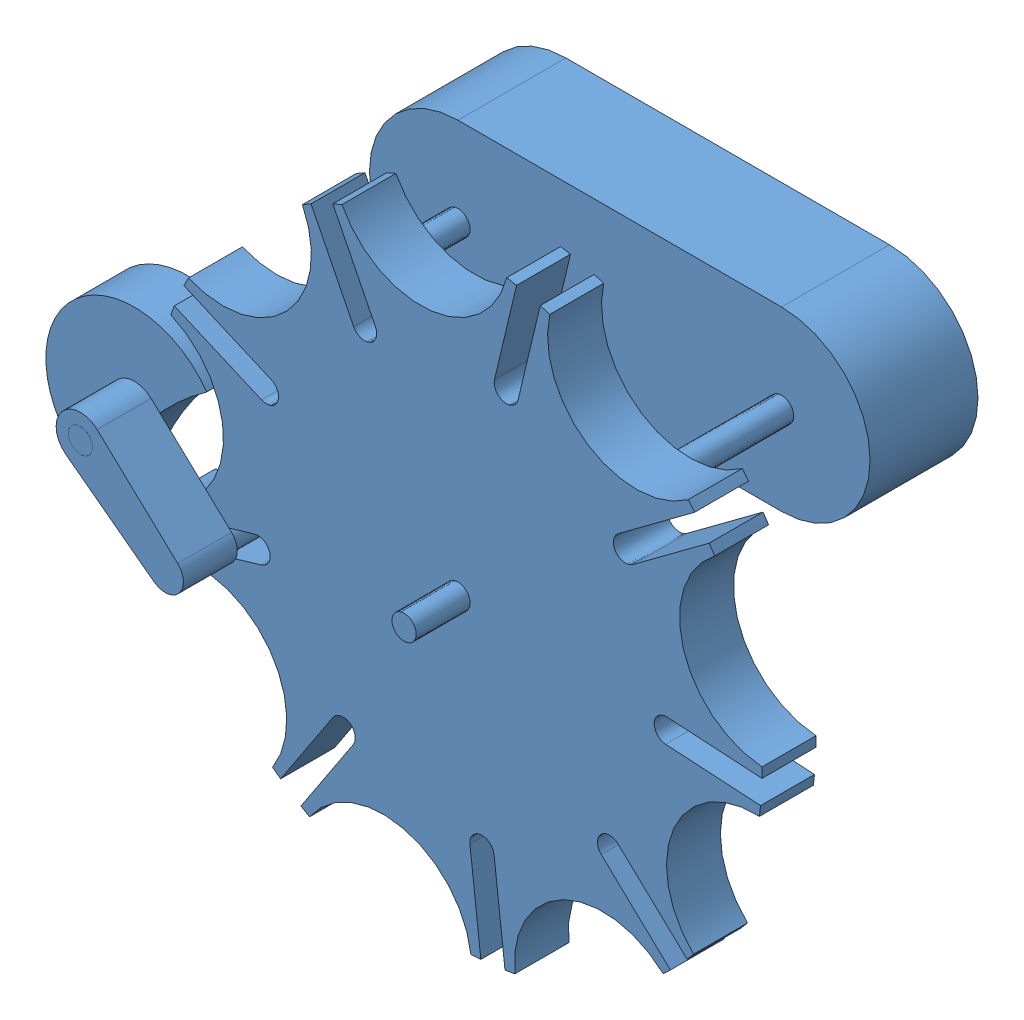
SolidWorks assembly Ensamble_Rueda_Malta, configuration Default. Lengths in mm.
Overall size (47.92 46.8 27).
3 component instances, 1 part files, 6 mates.
Components (placement in the parent):
- Rueda_Ginebra_4-1: Rueda_Ginebra_4 [Soporte] at origin size (27.85 9.85 27)
- Rueda_Ginebra_4-2: Rueda_Ginebra_4 [Disco_bloqueador] at (-24.1742 -16.908 0) x (-0.343011 -0.939331 0) z (0 0 1) size (9.85 11.73 6)
- Rueda_Ginebra_4-3: Rueda_Ginebra_4 [Default] x (0.802783 0.596272 0) z (0 0 1) size (33.17 33.65 3)
Mates (geometry in assembly coordinates):
- Concéntrica1: concentric aligned: circle of Rueda_Ginebra_4-1; circle of Rueda_Ginebra_4-2
- Coincidente2: coincident aligned: plane of Rueda_Ginebra_4-1 through (-18 0 3) normal (0 0 1); plane of Rueda_Ginebra_4-2 through (-18 0 3) normal (0 0 1)
- Coincidente4: coincident aligned: plane of Rueda_Ginebra_4-2 through (-11.4426 -5.0161 -3) normal (0 0 -1); plane of Rueda_Ginebra_4-3 through (0 0 -3) normal (0 0 -1)
- Concéntrica2: concentric aligned: circle of Rueda_Ginebra_4-1; circle of Rueda_Ginebra_4-3
- Tangente2: tangent: cylinder of Rueda_Ginebra_4-2 through (-18.6625 6.1206 -3) axis (0 0 1) radius 0.6766; plane of Rueda_Ginebra_4-3
- Tangente3: tangent anti-aligned: cylinder of Rueda_Ginebra_4-2 through (-13.2881 -3.9622 -3) axis (0 0 1) radius 0.6766; plane of Rueda_Ginebra_4-3 through (0.1933 -0.6484 -3) normal (-0.285744 0.958306 0)
